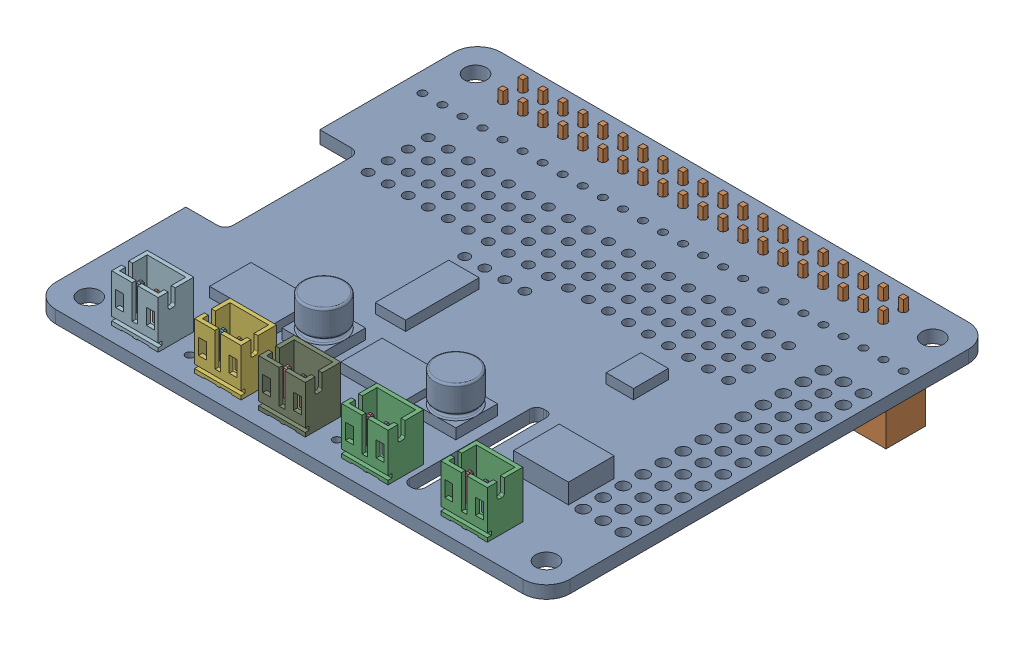
SolidWorks assembly AssembledAdafruitStepperHat, configuration Default. Lengths in mm.
Overall size (65.25 18.65 56.5).
7 component instances, 3 part files, 18 mates.
Components (placement in the parent):
- AdafruitStepperHat-1: AdafruitStepperHat [Default] at (71.9514 28.5864 47.8631) size (65.25 6.9 56.5)
- 40pin-1: 40pin [Default] at (3.861 28.5864 21.9797) x (0 0 -1) z (-1 0 0) size (5 14.05 51.4)
- JST PH2.0 2-1: JST PH2.0 2 [Standard] at (46.981 30.1864 75.1597) x (1 0 0) z (0 1 0) size (5.9 4.5 9.4)
- JST PH2.0 2-2: JST PH2.0 2 [Standard] at (15.731 30.1864 75.1597) x (1 0 0) z (0 1 0) size (5.9 4.5 9.4)
- JST PH2.0 2-3: JST PH2.0 2 [Standard] at (23.881 30.1864 75.1597) x (1 0 0) z (0 1 0) size (5.9 4.5 9.4)
- JST PH2.0 2-4: JST PH2.0 2 [Standard] at (5.231 30.1864 75.1597) x (1 0 0) z (0 1 0) size (5.9 4.5 9.4)
- JST PH2.0 2-5: JST PH2.0 2 [Standard] at (34.381 30.1864 75.1597) x (1 0 0) z (0 1 0) size (5.9 4.5 9.4)
Mates (geometry in assembly coordinates):
- Concentric34: concentric anti-aligned: line of 40pin-1 through (5.431 35.9364 23.2097) axis (0 -1 0); circle of AdafruitStepperHat-1
- Concentric35: concentric aligned: circle of AdafruitStepperHat-1; line of 40pin-1 through (53.691 28.2364 25.7497) axis (0 1 0)
- Coincident10: coincident anti-aligned: plane of AdafruitStepperHat-1 through (71.9514 28.5864 47.8631) normal (0 -1 0); plane of 40pin-1 through (29.561 28.5864 24.4797) normal (0 1 0)
- Deckungsgleich1: coincident anti-aligned: plane of AdafruitStepperHat-1 through (71.9514 30.1864 47.8631) normal (0 1 0); plane of JST PH2.0 2-1 through (49.931 30.1864 72.9097) normal (0 -1 0)
- Breite1: width anti-aligned: plane of AdafruitStepperHat-1 through (71.9514 30.1874 73.9597) normal (0 0 1); plane of JST PH2.0 2-1 through (71.9514 30.1874 72.9597) normal (0 0 -1); plane of AdafruitStepperHat-1 through (50.681 30.1864 73.2097) normal (0 0 -1); plane of JST PH2.0 2-1 through (51.181 30.1864 73.7097) normal (0 0 1)
- Breite3: width anti-aligned: plane of AdafruitStepperHat-1 through (47.681 30.1874 47.8631) normal (-1 0 0); plane of JST PH2.0 2-1 through (52.181 30.1874 47.8631) normal (1 0 0); plane of AdafruitStepperHat-1 through (51.181 30.1864 73.2097) normal (1 0 0); plane of JST PH2.0 2-1 through (48.681 30.1864 73.7097) normal (-1 0 0)
- Deckungsgleich2: coincident anti-aligned: plane of AdafruitStepperHat-1 through (71.9514 30.1864 47.8631) normal (0 1 0); plane of JST PH2.0 2-5 through (37.331 30.1864 72.9097) normal (0 -1 0)
- Deckungsgleich3: coincident anti-aligned: plane of AdafruitStepperHat-1 through (71.9514 30.1864 47.8631) normal (0 1 0); plane of JST PH2.0 2-4 through (8.181 30.1864 72.9097) normal (0 -1 0)
- Deckungsgleich4: coincident anti-aligned: plane of AdafruitStepperHat-1 through (71.9514 30.1864 47.8631) normal (0 1 0); plane of JST PH2.0 2-3 through (26.831 30.1864 72.9097) normal (0 -1 0)
- Deckungsgleich5: coincident anti-aligned: plane of AdafruitStepperHat-1 through (71.9514 30.1864 47.8631) normal (0 1 0); plane of JST PH2.0 2-2 through (18.681 30.1864 72.9097) normal (0 -1 0)
- Deckungsgleich6: coincident aligned: plane of JST PH2.0 2-4 through (8.181 33.1864 75.1597) normal (0 0 1); plane of JST PH2.0 2-5 through (37.331 33.1864 75.1597) normal (0 0 1)
- Deckungsgleich7: coincident aligned: plane of JST PH2.0 2-3 through (26.831 33.1864 75.1597) normal (0 0 1); plane of JST PH2.0 2-5 through (37.331 33.1864 75.1597) normal (0 0 1)
- Deckungsgleich8: coincident aligned: plane of JST PH2.0 2-2 through (18.681 33.1864 75.1597) normal (0 0 1); plane of JST PH2.0 2-5 through (37.331 33.1864 75.1597) normal (0 0 1)
- Deckungsgleich9: coincident aligned: plane of JST PH2.0 2-1 through (49.931 33.1864 75.1597) normal (0 0 1); plane of JST PH2.0 2-5 through (37.331 33.1864 75.1597) normal (0 0 1)
- Breite4: width anti-aligned: plane of AdafruitStepperHat-1 through (35.081 30.1874 47.8631) normal (-1 0 0); plane of JST PH2.0 2-5 through (39.581 30.1874 47.8631) normal (1 0 0); plane of AdafruitStepperHat-1 through (40.281 33.1864 72.9097) normal (1 0 0); plane of JST PH2.0 2-5 through (34.381 33.1864 72.9097) normal (-1 0 0)
- Breite5: width anti-aligned: plane of AdafruitStepperHat-1 through (24.581 30.1874 47.8631) normal (-1 0 0); plane of JST PH2.0 2-3 through (29.081 30.1874 47.8631) normal (1 0 0); plane of AdafruitStepperHat-1 through (29.781 33.1864 72.9097) normal (1 0 0); plane of JST PH2.0 2-3 through (23.881 33.1864 72.9097) normal (-1 0 0)
- Breite6: width anti-aligned: plane of AdafruitStepperHat-1 through (16.431 30.1874 47.8631) normal (-1 0 0); plane of JST PH2.0 2-2 through (20.931 30.1874 47.8631) normal (1 0 0); plane of AdafruitStepperHat-1 through (21.631 33.1864 72.9097) normal (1 0 0); plane of JST PH2.0 2-2 through (15.731 33.1864 72.9097) normal (-1 0 0)
- Breite7: width anti-aligned: plane of AdafruitStepperHat-1 through (5.931 30.1874 47.8631) normal (-1 0 0); plane of JST PH2.0 2-4 through (10.431 30.1874 47.8631) normal (1 0 0); plane of AdafruitStepperHat-1 through (11.131 33.1864 72.9097) normal (1 0 0); plane of JST PH2.0 2-4 through (5.231 33.1864 72.9097) normal (-1 0 0)
